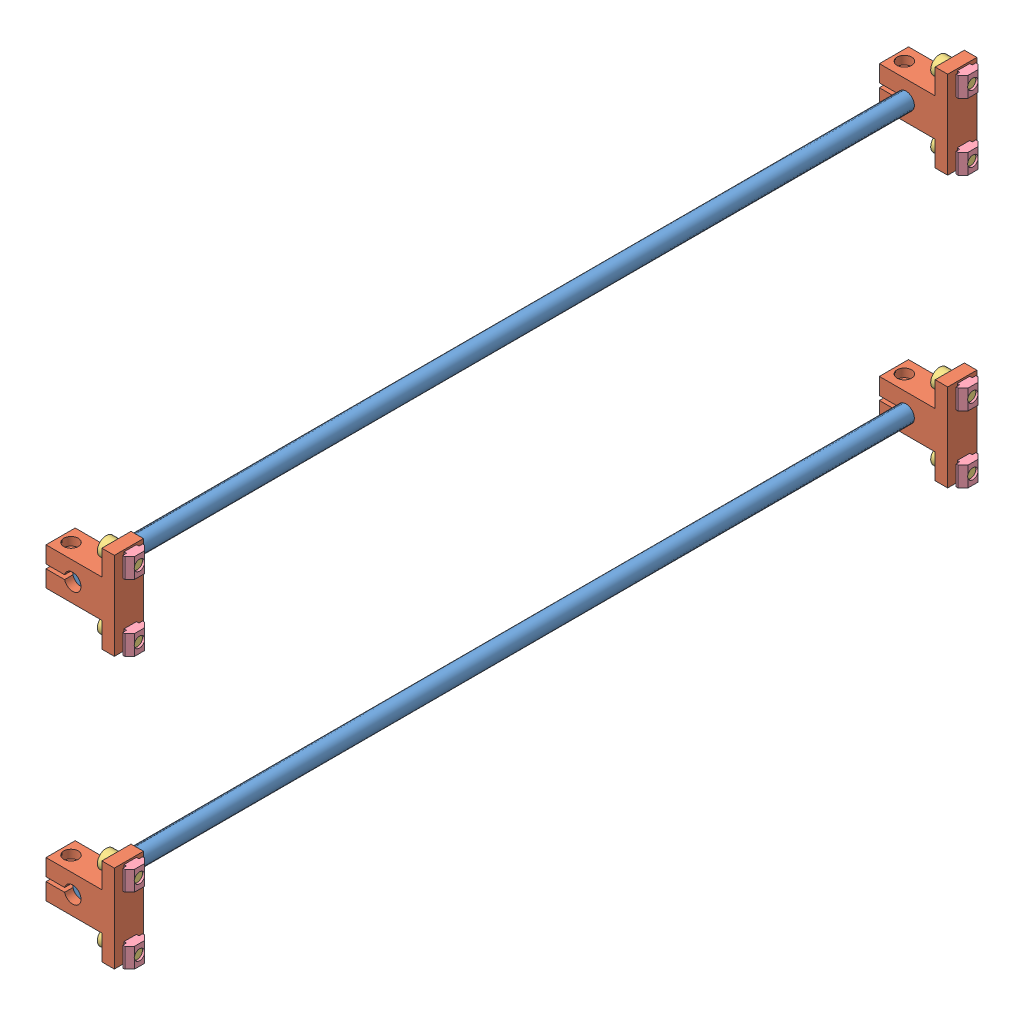
SolidWorks assembly 021Z轴活动机构-光轴-1, configuration Default. Lengths in mm.
Overall size (37.9 172 414).
22 component instances, 4 part files, 5 mates.
Components (placement in the parent):
- 光轴8mm_410mm-1: 光轴8mm_410mm [默认] at (210.8265 236.9371 45.0577) size (8 8 410)
- SK8-光轴固定座-1: SK8-光轴固定座 [默认] at (230.8265 236.9371 59.0577) x (0 -1 0) z (0 0 -1) size (42 32.8 14)
- SK8-光轴固定座-2: SK8-光轴固定座 [默认] at (230.8265 236.9371 459.0577) x (0 -1 0) z (0 0 -1) size (42 32.8 14)
- SK8-光轴固定座-3: SK8-光轴固定座 [默认] at (230.8265 366.9371 59.0577) x (0 -1 0) z (0 0 -1) size (42 32.8 14)
- 光轴8mm_410mm-2: 光轴8mm_410mm [默认] at (210.8265 366.9371 45.0577) size (8 8 410)
- SK8-光轴固定座-4: SK8-光轴固定座 [默认] at (230.8265 366.9371 459.0577) x (0 -1 0) z (0 0 -1) size (42 32.8 14)
- M5_10-9: M5_10 [默认] at (234.8265 382.9371 52.0577) x (0 0 -1) z (0 1 0) size (8.5 14.91 8.5)
- 欧标20M5滑块螺母-7: 欧标20M5滑块螺母 [默认] at (235.9265 378.1871 56.8077) x (0 1 0) z (0 0 1) size (9.5 4.5 9.5)
- 欧标20M5滑块螺母-9: 欧标20M5滑块螺母 [默认] at (235.9265 346.1871 56.8077) x (0 1 0) z (0 0 1) size (9.5 4.5 9.5)
- M5_10-10: M5_10 [默认] at (234.8265 350.9371 52.0577) x (0 0 -1) z (0 1 0) size (8.5 14.91 8.5)
- 欧标20M5滑块螺母-10: 欧标20M5滑块螺母 [默认] at (235.9265 248.1871 56.8077) x (0 1 0) z (0 0 1) size (9.5 4.5 9.5)
- 欧标20M5滑块螺母-11: 欧标20M5滑块螺母 [默认] at (235.9265 378.1871 456.8077) x (0 1 0) z (0 0 1) size (9.5 4.5 9.5)
- 欧标20M5滑块螺母-12: 欧标20M5滑块螺母 [默认] at (235.9265 248.1871 456.8077) x (0 1 0) z (0 0 1) size (9.5 4.5 9.5)
- M5_10-16: M5_10 [默认] at (234.8265 252.9371 52.0577) x (0 0 -1) z (0 1 0) size (8.5 14.91 8.5)
- M5_10-17: M5_10 [默认] at (234.8265 382.9371 452.0577) x (0 0 -1) z (0 1 0) size (8.5 14.91 8.5)
- M5_10-18: M5_10 [默认] at (234.8265 252.9371 452.0577) x (0 0 -1) z (0 1 0) size (8.5 14.91 8.5)
- 欧标20M5滑块螺母-13: 欧标20M5滑块螺母 [默认] at (235.9265 216.1871 56.8077) x (0 1 0) z (0 0 1) size (9.5 4.5 9.5)
- 欧标20M5滑块螺母-14: 欧标20M5滑块螺母 [默认] at (235.9265 346.1871 456.8077) x (0 1 0) z (0 0 1) size (9.5 4.5 9.5)
- 欧标20M5滑块螺母-15: 欧标20M5滑块螺母 [默认] at (235.9265 216.1871 456.8077) x (0 1 0) z (0 0 1) size (9.5 4.5 9.5)
- M5_10-13: M5_10 [默认] at (234.8265 220.9371 52.0577) x (0 0 -1) z (0 1 0) size (8.5 14.91 8.5)
- M5_10-14: M5_10 [默认] at (234.8265 350.9371 452.0577) x (0 0 -1) z (0 1 0) size (8.5 14.91 8.5)
- M5_10-15: M5_10 [默认] at (234.8265 220.9371 452.0577) x (0 0 -1) z (0 1 0) size (8.5 14.91 8.5)
Mates (geometry in assembly coordinates):
- 重合4: coincident: circle of 光轴8mm_410mm-1; circle of SK8-光轴固定座-1
- 重合6: coincident: plane of assembly; plane of assembly; plane of SK8-光轴固定座-3 through (224.8265 387.9371 45.0577) normal (-1 0 0); plane of M5_10-9 through (224.8265 382.9371 52.0577) normal (1 0 0)
- 同心2: concentric: cylinder of assembly; cylinder of assembly; cylinder of SK8-光轴固定座-3 through (198.0255 382.9371 52.0577) axis (1 0 0) radius 2.75; cylinder of M5_10-9 through (224.8265 382.9371 52.0577) axis (1 0 0) radius 2.5
- 同心11: concentric: cylinder of assembly; cylinder of assembly; cylinder of M5_10-9 through (224.8265 382.9371 52.0577) axis (1 0 0) radius 2.5; cylinder of 欧标20M5滑块螺母-7 through (235.9265 382.9371 52.0577) axis (-1 0 0) radius 2.5
- 距离3: distance = 1.8 mm: plane of assembly; plane of assembly; plane of SK8-光轴固定座-3 through (230.8265 345.9371 45.0577) normal (1 0 0); plane of 欧标20M5滑块螺母-7 through (232.6265 378.1871 56.8077) normal (-1 0 0)
